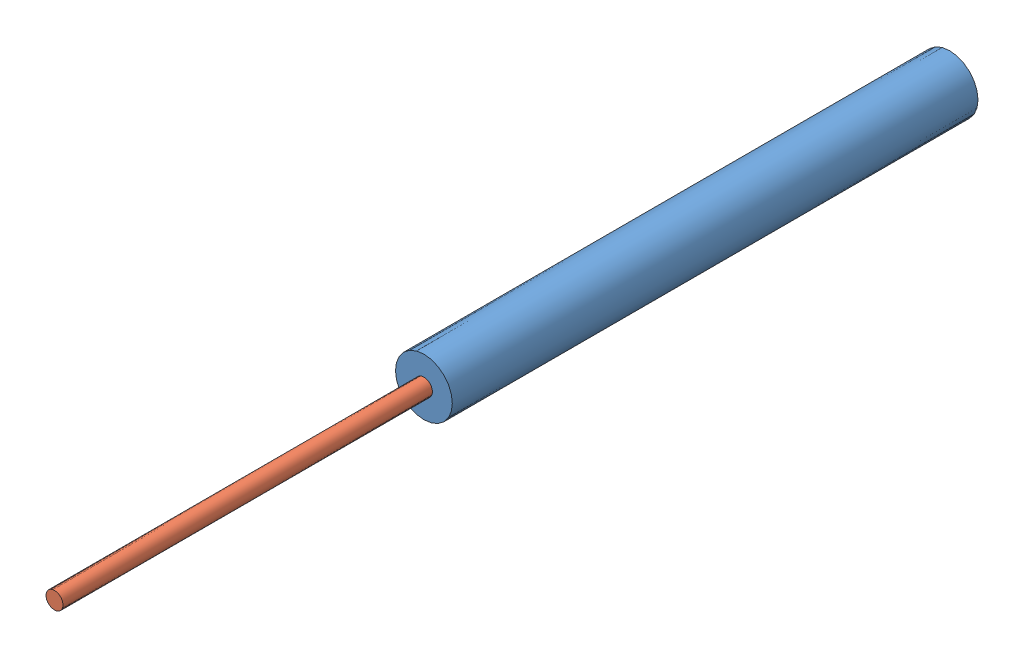
SolidWorks assembly Assem1, configuration Default. Lengths in mm.
Overall size (20 20 315).
2 component instances, 2 part files, 2 mates.
Components (placement in the parent):
- ống xylanh-1: ống xylanh [Default] at (80.9757 101.1309 40.0964) size (20 20 185)
- cơ cấu đẩy xylanh-2: cơ cấu đẩy xylanh [Default] at (80.9757 101.1309 215.0964) x (-0.985492 -0.169725 0) z (0 0 1) size (6 6 140)
Mates (geometry in assembly coordinates):
- Concentric1: concentric anti-aligned: cylinder of ống xylanh-1 through (80.9757 101.1309 75.0964) axis (0 0 1) radius 3; cylinder of cơ cấu đẩy xylanh-2 through (80.9757 101.1309 355.0964) axis (0 0 -1) radius 3
- LimitDistance1: limit distance = 130 mm aligned: plane of cơ cấu đẩy xylanh-2 through (80.9757 101.1309 355.0964) normal (0 0 1); plane of ống xylanh-1 through (80.9757 101.1309 225.0964) normal (0 0 1)
